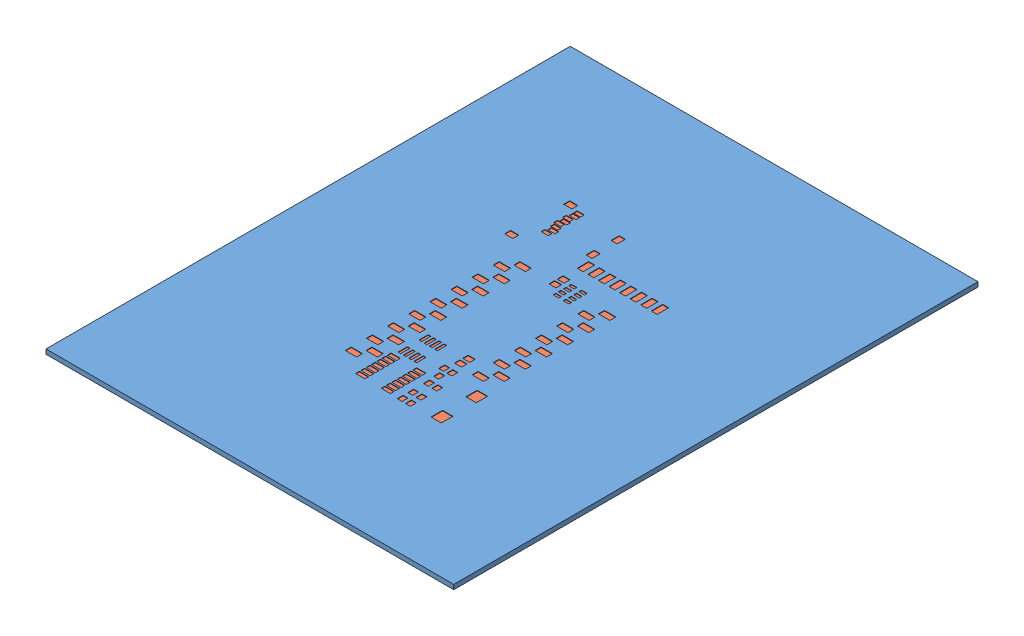
SolidWorks assembly SOLDER_PASTE, configuration Default. Lengths in mm.
Overall size (98 1.12 126).
2 component instances, 2 part files, 6 mates.
Components (placement in the parent):
- P4_SOLDER_STENCIL-1: P4_SOLDER_STENCIL [Default] at (-38 1.12 0) x (-1 0 0) z (0 0 1) size (98 1.12 126)
- P4_PCB_FOR_2.9_EPD-1: P4_PCB_FOR_2.9_EPD [Default] at (-38 0 0) size (38 1 66)
Mates (geometry in assembly coordinates):
- Coincident1: coincident anti-aligned: plane of P4_PCB_FOR_2.9_EPD-1 through (-38 0 0) normal (0 -1 0); plane of assembly through (0 0 0) normal (0 1 0)
- Coincident2: coincident aligned: plane of P4_PCB_FOR_2.9_EPD-1 through (-38 1 0) normal (0 0 1); plane of assembly through (0 0 0) normal (0 0 1)
- Coincident3: coincident aligned: plane of P4_PCB_FOR_2.9_EPD-1 through (0 1 0) normal (1 0 0); plane of assembly through (0 0 0) normal (1 0 0)
- LimitDistance1: limit distance = 0 mm anti-aligned: plane of P4_SOLDER_STENCIL-1 through (-38 1 0) normal (0 -1 0); plane of P4_PCB_FOR_2.9_EPD-1 through (-38 1 0) normal (0 1 0)
- Coincident5: coincident anti-aligned: plane of P4_SOLDER_STENCIL-1 through (-38 0 0) normal (0 0 -1); plane of P4_PCB_FOR_2.9_EPD-1 through (-38 1 0) normal (0 0 1)
- Coincident6: coincident anti-aligned: plane of P4_SOLDER_STENCIL-1 through (0 0 0) normal (-1 0 0); plane of P4_PCB_FOR_2.9_EPD-1 through (0 1 0) normal (1 0 0)
